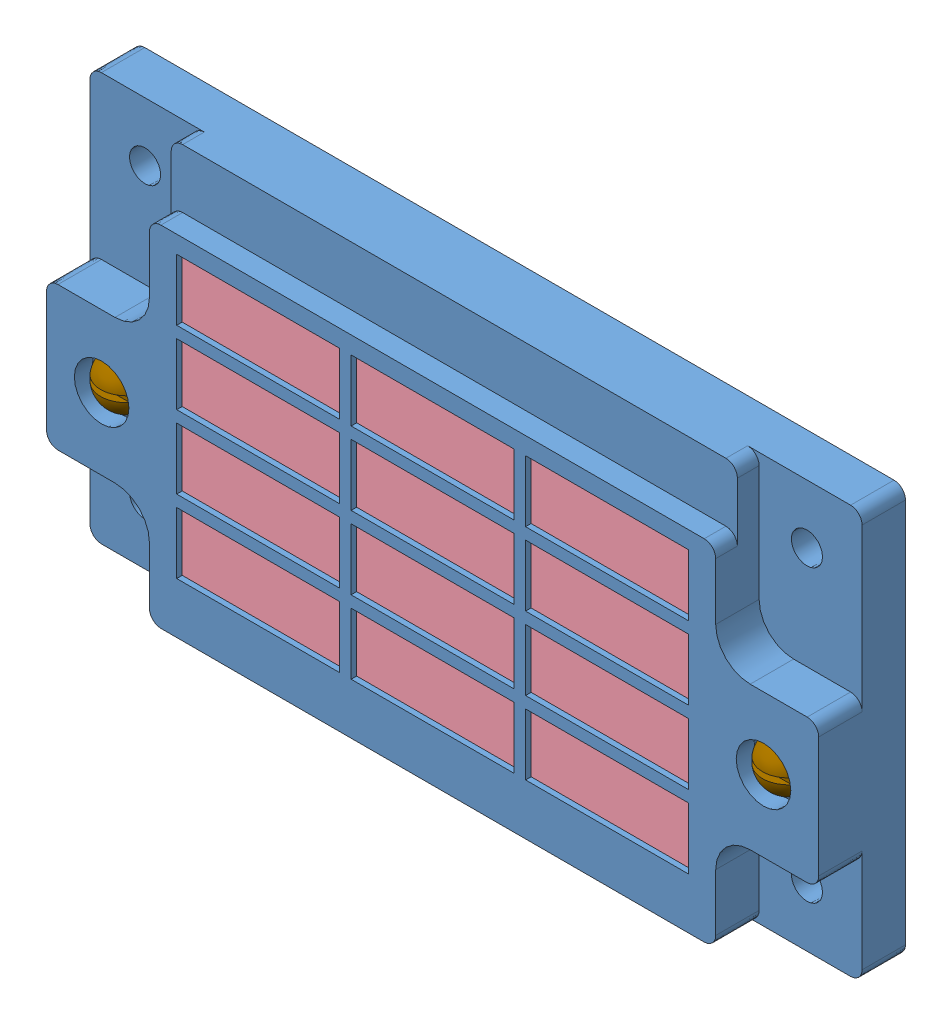
SolidWorks assembly Caution Lights Panel, configuration Default. Lengths in mm.
Overall size (106.68 56.39 15.2).
72 component instances, 9 part files, 31 mates.
Components (placement in the parent):
- Caution Lights Panel Chassis-1: Caution Lights Panel Chassis [Default] at origin size (106.68 56.39 12)
- Caution Lights Panel Legend Diffuser-1: Caution Lights Panel Legend Diffuser [Amber] at (0 0 10.349) x (-1 0 0) z (0 0 -1) size (23.01 9.01 0.13)
- Caution Lights Panel Legend Diffuser-2: Caution Lights Panel Legend Diffuser [Amber] at (0 10.1092 10.349) x (-1 0 0) z (0 0 -1) size (23.01 9.01 0.13)
- Caution Lights Panel Legend Diffuser-3: Caution Lights Panel Legend Diffuser [Amber] at (0 20.2184 10.349) x (-1 0 0) z (0 0 -1) size (23.01 9.01 0.13)
- Caution Lights Panel Legend Diffuser-4: Caution Lights Panel Legend Diffuser [Amber] at (0 30.3276 10.349) x (-1 0 0) z (0 0 -1) size (23.01 9.01 0.13)
- Caution Lights Panel Legend Diffuser-5: Caution Lights Panel Legend Diffuser [Amber] at (-24.1046 0 10.349) x (-1 0 0) z (0 0 -1) size (23.01 9.01 0.13)
- Caution Lights Panel Legend Diffuser-6: Caution Lights Panel Legend Diffuser [Amber] at (-24.1046 10.1092 10.349) x (-1 0 0) z (0 0 -1) size (23.01 9.01 0.13)
- Caution Lights Panel Legend Diffuser-7: Caution Lights Panel Legend Diffuser [Amber] at (-24.1046 20.2184 10.349) x (-1 0 0) z (0 0 -1) size (23.01 9.01 0.13)
- Caution Lights Panel Legend Diffuser-8: Caution Lights Panel Legend Diffuser [Amber] at (-24.1046 30.3276 10.349) x (-1 0 0) z (0 0 -1) size (23.01 9.01 0.13)
- Caution Lights Panel Legend Diffuser-9: Caution Lights Panel Legend Diffuser [Amber] at (-48.2092 0 10.349) x (-1 0 0) z (0 0 -1) size (23.01 9.01 0.13)
- Caution Lights Panel Legend Diffuser-10: Caution Lights Panel Legend Diffuser [Amber] at (-48.2092 10.1092 10.349) x (-1 0 0) z (0 0 -1) size (23.01 9.01 0.13)
- Caution Lights Panel Legend Diffuser-11: Caution Lights Panel Legend Diffuser [Amber] at (-48.2092 20.2184 10.349) x (-1 0 0) z (0 0 -1) size (23.01 9.01 0.13)
- Caution Lights Panel Legend Diffuser-12: Caution Lights Panel Legend Diffuser [Amber] at (-48.2092 30.3276 10.349) x (-1 0 0) z (0 0 -1) size (23.01 9.01 0.13)
- Caution Lights Panel Legend-1: Caution Lights Panel Legend [CK SEAT] at (0 0 10.476) x (-1 0 0) z (0 0 -1) size (23.01 9.01 0.13)
- Caution Lights Panel Legend-2: Caution Lights Panel Legend [FCS HOT] at (0 10.1092 10.476) x (-1 0 0) z (0 0 -1) size (23.01 9.01 0.13)
- Caution Lights Panel Legend-3: Caution Lights Panel Legend [FUEL LO] at (0 20.2184 10.476) x (-1 0 0) z (0 0 -1) size (23.01 9.01 0.13)
- Caution Lights Panel Legend-4: Caution Lights Panel Legend [L GEN] at (0 30.3276 10.476) x (-1 0 0) z (0 0 -1) size (23.01 9.01 0.13)
- Caution Lights Panel Legend-5: Caution Lights Panel Legend [APU ACC] at (-24.1046 0 10.476) x (-1 0 0) z (0 0 -1) size (23.01 9.01 0.13)
- Caution Lights Panel Legend-6: Caution Lights Panel Legend [GEN TIE] at (-24.1046 10.1092 10.476) x (-1 0 0) z (0 0 -1) size (23.01 9.01 0.13)
- Caution Lights Panel Legend-7: Caution Lights Panel Legend [FCES] at (-24.1046 20.2184 10.476) x (-1 0 0) z (0 0 -1) size (23.01 9.01 0.13)
- Caution Lights Panel Legend-8: Caution Lights Panel Legend [R GEN] at (-24.1046 30.3276 10.476) x (-1 0 0) z (0 0 -1) size (23.01 9.01 0.13)
- Caution Lights Panel Legend-9: Caution Lights Panel Legend [BATT SW] at (-48.2092 0 10.476) x (-1 0 0) z (0 0 -1) size (23.01 9.01 0.13)
- Caution Lights Panel Legend-10: Caution Lights Panel Legend [BLANK] at (-48.2092 10.1092 10.476) x (-1 0 0) z (0 0 -1) size (23.01 9.01 0.13)
- Caution Lights Panel Legend-11: Caution Lights Panel Legend [BLANK] at (-48.2092 20.2184 10.476) x (-1 0 0) z (0 0 -1) size (23.01 9.01 0.13)
- Caution Lights Panel Legend-12: Caution Lights Panel Legend [BLANK] at (-48.2092 30.3276 10.476) x (-1 0 0) z (0 0 -1) size (23.01 9.01 0.13)
- Caution Lights Panel Legend Cover-1: Caution Lights Panel Legend Cover [Default] at (0 0 11.238) x (-1 0 0) z (0 0 -1) size (23.01 9.01 0.76)
- Caution Lights Panel Legend Cover-2: Caution Lights Panel Legend Cover [Default] at (0 10.1092 11.238) x (-1 0 0) z (0 0 -1) size (23.01 9.01 0.76)
- Caution Lights Panel Legend Cover-3: Caution Lights Panel Legend Cover [Default] at (0 20.2184 11.238) x (-1 0 0) z (0 0 -1) size (23.01 9.01 0.76)
- Caution Lights Panel Legend Cover-4: Caution Lights Panel Legend Cover [Default] at (0 30.3276 11.238) x (-1 0 0) z (0 0 -1) size (23.01 9.01 0.76)
- Caution Lights Panel Legend Cover-5: Caution Lights Panel Legend Cover [Default] at (-24.1046 0 11.238) x (-1 0 0) z (0 0 -1) size (23.01 9.01 0.76)
- Caution Lights Panel Legend Cover-6: Caution Lights Panel Legend Cover [Default] at (-24.1046 10.1092 11.238) x (-1 0 0) z (0 0 -1) size (23.01 9.01 0.76)
- Caution Lights Panel Legend Cover-7: Caution Lights Panel Legend Cover [Default] at (-24.1046 20.2184 11.238) x (-1 0 0) z (0 0 -1) size (23.01 9.01 0.76)
- Caution Lights Panel Legend Cover-8: Caution Lights Panel Legend Cover [Default] at (-24.1046 30.3276 11.238) x (-1 0 0) z (0 0 -1) size (23.01 9.01 0.76)
- Caution Lights Panel Legend Cover-9: Caution Lights Panel Legend Cover [Default] at (-48.2092 0 11.238) x (-1 0 0) z (0 0 -1) size (23.01 9.01 0.76)
- Caution Lights Panel Legend Cover-10: Caution Lights Panel Legend Cover [Default] at (-48.2092 10.1092 11.238) x (-1 0 0) z (0 0 -1) size (23.01 9.01 0.76)
- Caution Lights Panel Legend Cover-11: Caution Lights Panel Legend Cover [Default] at (-48.2092 20.2184 11.238) x (-1 0 0) z (0 0 -1) size (23.01 9.01 0.76)
- Caution Lights Panel Legend Cover-12: Caution Lights Panel Legend Cover [Default] at (-48.2092 30.3276 11.238) x (-1 0 0) z (0 0 -1) size (23.01 9.01 0.76)
- Caution Lights Panel PCB-1: Caution Lights Panel PCB [Default] x (-1 0 0) z (0 0 -1) size (81.88 39.82 1.59)
- IN-S63AT5UW - LED, 0603, WHITE, 3V, 5mA, 900mcd-1: IN-S63AT5UW - LED, 0603, WHITE, 3V, 5mA, 900mcd [Default] at (-3076.9848 1134.3057 0.0064) size (0.79 1.61 0.71)
- IN-S63AT5UW - LED, 0603, WHITE, 3V, 5mA, 900mcd-2: IN-S63AT5UW - LED, 0603, WHITE, 3V, 5mA, 900mcd [Default] at (-3087.2928 1134.3057 0.0064) size (0.79 1.61 0.71)
- IN-S63AT5UW - LED, 0603, WHITE, 3V, 5mA, 900mcd-3: IN-S63AT5UW - LED, 0603, WHITE, 3V, 5mA, 900mcd [Default] at (-3087.2928 1144.4149 0.0064) size (0.79 1.61 0.71)
- IN-S63AT5UW - LED, 0603, WHITE, 3V, 5mA, 900mcd-4: IN-S63AT5UW - LED, 0603, WHITE, 3V, 5mA, 900mcd [Default] at (-3087.2928 1154.5241 0.0064) size (0.79 1.61 0.71)
- IN-S63AT5UW - LED, 0603, WHITE, 3V, 5mA, 900mcd-5: IN-S63AT5UW - LED, 0603, WHITE, 3V, 5mA, 900mcd [Default] at (-3087.2928 1164.6333 0.0064) size (0.79 1.61 0.71)
- IN-S63AT5UW - LED, 0603, WHITE, 3V, 5mA, 900mcd-6: IN-S63AT5UW - LED, 0603, WHITE, 3V, 5mA, 900mcd [Default] at (-3111.3974 1134.3057 0.0064) size (0.79 1.61 0.71)
- IN-S63AT5UW - LED, 0603, WHITE, 3V, 5mA, 900mcd-7: IN-S63AT5UW - LED, 0603, WHITE, 3V, 5mA, 900mcd [Default] at (-3111.3974 1144.4149 0.0064) size (0.79 1.61 0.71)
- IN-S63AT5UW - LED, 0603, WHITE, 3V, 5mA, 900mcd-8: IN-S63AT5UW - LED, 0603, WHITE, 3V, 5mA, 900mcd [Default] at (-3111.3974 1154.5241 0.0064) size (0.79 1.61 0.71)
- IN-S63AT5UW - LED, 0603, WHITE, 3V, 5mA, 900mcd-9: IN-S63AT5UW - LED, 0603, WHITE, 3V, 5mA, 900mcd [Default] at (-3111.3974 1164.6333 0.0064) size (0.79 1.61 0.71)
- IN-S63AT5UW - LED, 0603, WHITE, 3V, 5mA, 900mcd-10: IN-S63AT5UW - LED, 0603, WHITE, 3V, 5mA, 900mcd [Default] at (-3135.502 1134.3057 0.0064) size (0.79 1.61 0.71)
- IN-S63AT5UW - LED, 0603, WHITE, 3V, 5mA, 900mcd-11: IN-S63AT5UW - LED, 0603, WHITE, 3V, 5mA, 900mcd [Default] at (-3135.502 1144.4149 0.0064) size (0.79 1.61 0.71)
- IN-S63AT5UW - LED, 0603, WHITE, 3V, 5mA, 900mcd-12: IN-S63AT5UW - LED, 0603, WHITE, 3V, 5mA, 900mcd [Default] at (-3135.502 1154.5241 0.0064) size (0.79 1.61 0.71)
- IN-S63AT5UW - LED, 0603, WHITE, 3V, 5mA, 900mcd-13: IN-S63AT5UW - LED, 0603, WHITE, 3V, 5mA, 900mcd [Default] at (-3135.502 1164.6333 0.0064) size (0.79 1.61 0.71)
- IN-S63AT5UW - LED, 0603, WHITE, 3V, 5mA, 900mcd-14: IN-S63AT5UW - LED, 0603, WHITE, 3V, 5mA, 900mcd [Default] at (-3076.9848 1144.4149 0.0064) size (0.79 1.61 0.71)
- IN-S63AT5UW - LED, 0603, WHITE, 3V, 5mA, 900mcd-15: IN-S63AT5UW - LED, 0603, WHITE, 3V, 5mA, 900mcd [Default] at (-3076.9848 1154.5241 0.0064) size (0.79 1.61 0.71)
- IN-S63AT5UW - LED, 0603, WHITE, 3V, 5mA, 900mcd-16: IN-S63AT5UW - LED, 0603, WHITE, 3V, 5mA, 900mcd [Default] at (-3076.9848 1164.6333 0.0064) size (0.79 1.61 0.71)
- IN-S63AT5UW - LED, 0603, WHITE, 3V, 5mA, 900mcd-17: IN-S63AT5UW - LED, 0603, WHITE, 3V, 5mA, 900mcd [Default] at (-3101.0894 1134.3057 0.0064) size (0.79 1.61 0.71)
- IN-S63AT5UW - LED, 0603, WHITE, 3V, 5mA, 900mcd-18: IN-S63AT5UW - LED, 0603, WHITE, 3V, 5mA, 900mcd [Default] at (-3101.0894 1144.4149 0.0064) size (0.79 1.61 0.71)
- IN-S63AT5UW - LED, 0603, WHITE, 3V, 5mA, 900mcd-19: IN-S63AT5UW - LED, 0603, WHITE, 3V, 5mA, 900mcd [Default] at (-3101.0894 1154.5241 0.0064) size (0.79 1.61 0.71)
- IN-S63AT5UW - LED, 0603, WHITE, 3V, 5mA, 900mcd-20: IN-S63AT5UW - LED, 0603, WHITE, 3V, 5mA, 900mcd [Default] at (-3101.0894 1164.6333 0.0064) size (0.79 1.61 0.71)
- IN-S63AT5UW - LED, 0603, WHITE, 3V, 5mA, 900mcd-21: IN-S63AT5UW - LED, 0603, WHITE, 3V, 5mA, 900mcd [Default] at (-3125.194 1134.3057 0.0064) size (0.79 1.61 0.71)
- IN-S63AT5UW - LED, 0603, WHITE, 3V, 5mA, 900mcd-22: IN-S63AT5UW - LED, 0603, WHITE, 3V, 5mA, 900mcd [Default] at (-3125.194 1144.4149 0.0064) size (0.79 1.61 0.71)
- IN-S63AT5UW - LED, 0603, WHITE, 3V, 5mA, 900mcd-23: IN-S63AT5UW - LED, 0603, WHITE, 3V, 5mA, 900mcd [Default] at (-3125.194 1154.5241 0.0064) size (0.79 1.61 0.71)
- IN-S63AT5UW - LED, 0603, WHITE, 3V, 5mA, 900mcd-24: IN-S63AT5UW - LED, 0603, WHITE, 3V, 5mA, 900mcd [Default] at (-3125.194 1164.6333 0.0064) size (0.79 1.61 0.71)
- 93365A110_BRASS HEAT-SET INSERT FOR PLASTICS_2-56-1: 93365A110_BRASS HEAT-SET INSERT FOR PLASTICS_2-56 [Default] at (-3067.85 1166.8237 0) x (-0.923728 -0.383049 0) z (0.383049 -0.923728 0) size (3.58 3.09 3.58)
- 93365A110_BRASS HEAT-SET INSERT FOR PLASTICS_2-56-2: 93365A110_BRASS HEAT-SET INSERT FOR PLASTICS_2-56 [Default] at (-3067.85 1132.0877 0) x (-0.85131 -0.524663 0) z (0.524663 -0.85131 0) size (3.58 3.09 3.58)
- 93365A110_BRASS HEAT-SET INSERT FOR PLASTICS_2-56-3: 93365A110_BRASS HEAT-SET INSERT FOR PLASTICS_2-56 [Default] at (-3144.6368 1132.0877 0) x (-0.777574 -0.628792 0) z (0.628792 -0.777574 0) size (3.58 3.09 3.58)
- 93365A110_BRASS HEAT-SET INSERT FOR PLASTICS_2-56-4: 93365A110_BRASS HEAT-SET INSERT FOR PLASTICS_2-56 [Default] at (-3144.6368 1166.8237 0) x (-0.715577 -0.698533 0) z (0.698533 -0.715577 0) size (3.58 3.09 3.58)
- 94070A076 - PHS, 2-56 X .1875, BRASS-1: 94070A076 - PHS, 2-56 X .1875, BRASS [94070A076] at (-3144.6368 1132.0877 3.175) x (-0.923728 -0.383049 0) z (0 0 -1) size (4.24 4.24 6.25)
- 94070A076 - PHS, 2-56 X .1875, BRASS-2: 94070A076 - PHS, 2-56 X .1875, BRASS [94070A076] at (-3067.8408 1132.0877 3.175) x (-0.85131 -0.524663 0) z (0 0 -1) size (4.24 4.24 6.25)
- 94070A076 - PHS, 2-56 X .1875, BRASS-3: 94070A076 - PHS, 2-56 X .1875, BRASS [94070A076] at (-3067.8408 1166.8237 3.175) x (-0.777574 -0.628792 0) z (0 0 -1) size (4.24 4.24 6.25)
- 94070A076 - PHS, 2-56 X .1875, BRASS-4: 94070A076 - PHS, 2-56 X .1875, BRASS [94070A076] at (-3144.6368 1166.8237 3.175) x (-0.715577 -0.698533 0) z (0 0 -1) size (4.24 4.24 6.25)
- 90276A143 - RHS, SLOTTED, 6-32 X .1875, STEEL, ZINC-PLATED-1: 90276A143 - RHS, SLOTTED, 6-32 X .1875, STEEL, ZINC-PLATED [90276A143] at (-3151.9588 1147.1257 9.5362) size (6.6 6.6 7.62)
- 90276A143 - RHS, SLOTTED, 6-32 X .1875, STEEL, ZINC-PLATED-2: 90276A143 - RHS, SLOTTED, 6-32 X .1875, STEEL, ZINC-PLATED [90276A143] at (-3060.5188 1147.1257 9.5362) size (6.6 6.6 7.62)
Mates (geometry in assembly coordinates):
- InPlace1: in place: plane of Caution Lights Panel Chassis-1 through (-3054.4863 1124.5832 0) normal (0 0 -1); plane of Caution Lights Panel PCB-1 through (0 0 0) normal (0 0 -1); moOrthogonalPlaneRef_w of Caution Lights Panel Chassis-1 through (-3054.4863 1124.5832 0) normal (0 0 -1); line of Caution Lights Panel PCB-1 through (-55 0 0) axis (0 0 1); plane of Caution Lights Panel Chassis-1 through (-3054.4863 1124.5832 0) normal (0 0 -1); plane of Caution Lights Panel PCB-1 through (0 0 0) normal (-1 0 0); plane of Caution Lights Panel Chassis-1 through (-3054.4863 1124.5832 0) normal (0 0 -1); unknown of Caution Lights Panel PCB-1
- Coincident1: coincident aligned: plane of Caution Lights Panel Chassis-1; plane of Caution Lights Panel PCB-1
- Coincident2: coincident aligned: moOrthogonalPlaneRef_w of Caution Lights Panel Chassis-1 through (0 0 0) normal (0 1 0); plane of Caution Lights Panel PCB-1 through (0 0 0) normal (0 1 0)
- Coincident3: coincident anti-aligned: moOrthogonalPlaneRef_w of Caution Lights Panel Chassis-1 through (0 0 0) normal (1 0 0); plane of Caution Lights Panel PCB-1 through (0 0 0) normal (-1 0 0)
- Concentric1: concentric aligned: cone of Caution Lights Panel Chassis-1 through (-3067.85 1166.8237 0) axis (0 0 1); cone of 93365A110_BRASS HEAT-SET INSERT FOR PLASTICS_2-56-1 through (-3067.85 1166.8237 1.11) axis (0 0 1)
- Coincident4: coincident aligned: plane of Caution Lights Panel Chassis-1 through (-3054.4863 1124.5832 0) normal (0 0 -1); plane of 93365A110_BRASS HEAT-SET INSERT FOR PLASTICS_2-56-1 through (-3066.1958 1167.5096 0) normal (0 0 -1)
- Concentric2: concentric aligned: cone of Caution Lights Panel Chassis-1 through (-3067.85 1132.0877 0) axis (0 0 1); cone of 93365A110_BRASS HEAT-SET INSERT FOR PLASTICS_2-56-2 through (-3067.85 1132.0877 1.11) axis (0 0 1)
- Coincident5: coincident aligned: plane of Caution Lights Panel Chassis-1 through (-3054.4863 1124.5832 0) normal (0 0 -1); plane of 93365A110_BRASS HEAT-SET INSERT FOR PLASTICS_2-56-2 through (-3066.3255 1133.0272 0) normal (0 0 -1)
- Concentric3: concentric aligned: cone of Caution Lights Panel Chassis-1 through (-3144.6368 1132.0877 0) axis (0 0 1); cone of 93365A110_BRASS HEAT-SET INSERT FOR PLASTICS_2-56-3 through (-3144.6368 1132.0877 1.11) axis (0 0 1)
- Coincident6: coincident aligned: plane of Caution Lights Panel Chassis-1 through (-3054.4863 1124.5832 0) normal (0 0 -1); plane of 93365A110_BRASS HEAT-SET INSERT FOR PLASTICS_2-56-3 through (-3143.2444 1133.2137 0) normal (0 0 -1)
- Concentric4: concentric aligned: cone of Caution Lights Panel Chassis-1 through (-3144.6368 1166.8237 0) axis (0 0 1); cone of 93365A110_BRASS HEAT-SET INSERT FOR PLASTICS_2-56-4 through (-3144.6368 1166.8237 1.11) axis (0 0 1)
- Coincident7: coincident aligned: plane of Caution Lights Panel Chassis-1 through (-3054.4863 1124.5832 0) normal (0 0 -1); plane of 93365A110_BRASS HEAT-SET INSERT FOR PLASTICS_2-56-4 through (-3143.3554 1168.0746 0) normal (0 0 -1)
- Concentric5: concentric anti-aligned: cylinder of Caution Lights Panel PCB-1 through (-3144.6368 1132.0877 -1.5875) axis (0 0 -1) radius 1.35; cylinder of 94070A076 - PHS, 2-56 X .1875, BRASS-1 through (-3144.6368 1132.0877 3.175) axis (0 0 1) radius 2.1209
- Coincident8: coincident anti-aligned: plane of Caution Lights Panel PCB-1 through (0 0 -1.5875) normal (0 0 -1); plane of 94070A076 - PHS, 2-56 X .1875, BRASS-1 through (-3144.6368 1132.0877 -1.5875) normal (0 0 1)
- Concentric6: concentric anti-aligned: cylinder of Caution Lights Panel PCB-1 through (-3067.8408 1132.0877 -1.5875) axis (0 0 -1) radius 1.35; cylinder of 94070A076 - PHS, 2-56 X .1875, BRASS-2 through (-3067.8408 1132.0877 3.175) axis (0 0 1) radius 2.1209
- Coincident9: coincident anti-aligned: plane of Caution Lights Panel PCB-1 through (0 0 -1.5875) normal (0 0 -1); plane of 94070A076 - PHS, 2-56 X .1875, BRASS-2 through (-3067.8408 1132.0877 -1.5875) normal (0 0 1)
- Concentric7: concentric anti-aligned: cylinder of Caution Lights Panel PCB-1 through (-3067.8408 1166.8237 -1.5875) axis (0 0 -1) radius 1.35; cylinder of 94070A076 - PHS, 2-56 X .1875, BRASS-3 through (-3067.8408 1166.8237 3.175) axis (0 0 1) radius 2.1209
- Coincident10: coincident anti-aligned: plane of Caution Lights Panel PCB-1 through (0 0 -1.5875) normal (0 0 -1); plane of 94070A076 - PHS, 2-56 X .1875, BRASS-3 through (-3067.8408 1166.8237 -1.5875) normal (0 0 1)
- Concentric8: concentric anti-aligned: cylinder of Caution Lights Panel PCB-1 through (-3144.6368 1166.8237 -1.5875) axis (0 0 -1) radius 1.35; cylinder of 94070A076 - PHS, 2-56 X .1875, BRASS-4 through (-3144.6368 1166.8237 3.175) axis (0 0 1) radius 2.1209
- Coincident11: coincident anti-aligned: plane of Caution Lights Panel PCB-1 through (0 0 -1.5875) normal (0 0 -1); plane of 94070A076 - PHS, 2-56 X .1875, BRASS-4 through (-3144.6368 1166.8237 -1.5875) normal (0 0 1)
- Coincident12: coincident anti-aligned: plane of Caution Lights Panel PCB-1 through (0 0 0) normal (0 0 1); plane of IN-S63AT5UW - LED, 0603, WHITE, 3V, 5mA, 900mcd-1 through (-3077.381 1135.1147 0) normal (0 0 -1)
- Parallel1: parallel aligned: plane of Caution Lights Panel PCB-1 through (-3065.3008 1169.3637 -1.5875) normal (1 0 0); plane of IN-S63AT5UW - LED, 0603, WHITE, 3V, 5mA, 900mcd-1 through (-3076.5911 1135.0994 0.2984) normal (1 0 0)
- Width1: width anti-aligned: plane of Caution Lights Panel Legend-1 through (-3070.6348 1129.8017 10.349) normal (0 -1 0); plane of Caution Lights Panel Legend-1 through (-3093.6428 1138.8097 10.349) normal (0 1 0); plane of IN-S63AT5UW - LED, 0603, WHITE, 3V, 5mA, 900mcd-1 through (-3077.381 1135.1058 0.3109) normal (0 1 0); plane of IN-S63AT5UW - LED, 0603, WHITE, 3V, 5mA, 900mcd-1 through (-3077.381 1133.5056 0.3109) normal (0 -1 0)
- Distance1: distance = 6.35 mm aligned: plane of IN-S63AT5UW - LED, 0603, WHITE, 3V, 5mA, 900mcd-1 through (-3076.9848 1134.3057 0.0064) normal (1 0 0); plane of Caution Lights Panel Legend-1 through (-3070.6348 1138.8097 10.349) normal (1 0 0)
- Coincident14: coincident aligned: plane of IN-S63AT5UW - LED, 0603, WHITE, 3V, 5mA, 900mcd-1 through (-3077.3942 1133.8352 0.7074) normal (0 0 1); plane of IN-S63AT5UW - LED, 0603, WHITE, 3V, 5mA, 900mcd-2 through (-3087.7022 1133.8352 0.7074) normal (0 0 1)
- Coincident15: coincident aligned: plane of IN-S63AT5UW - LED, 0603, WHITE, 3V, 5mA, 900mcd-1 through (-3077.3942 1133.7594 0.2943) normal (0 -0.99863 0.052336); plane of IN-S63AT5UW - LED, 0603, WHITE, 3V, 5mA, 900mcd-2 through (-3087.7022 1133.7594 0.2943) normal (0 -0.99863 0.052336)
- Distance2: distance = 6.35 mm anti-aligned: plane of IN-S63AT5UW - LED, 0603, WHITE, 3V, 5mA, 900mcd-2 through (-3087.2928 1134.3057 0.0064) normal (1 0 0); plane of Caution Lights Panel Legend-1 through (-3093.6428 1129.8017 10.349) normal (-1 0 0)
- Concentric10: concentric anti-aligned: cylinder of Caution Lights Panel Chassis-1 through (-3151.9588 1147.1257 12) axis (0 0 1) radius 3.7706; cylinder of 90276A143 - RHS, SLOTTED, 6-32 X .1875, STEEL, ZINC-PLATED-1 through (-3151.9588 1147.1257 12.1524) axis (0 0 -1) radius 3.302
- Coincident17: coincident anti-aligned: plane of Caution Lights Panel Chassis-1 through (-3149.8061 1147.1257 9.5362) normal (0 0 1); plane of 90276A143 - RHS, SLOTTED, 6-32 X .1875, STEEL, ZINC-PLATED-1 through (-3151.9588 1147.1257 9.5362) normal (0 0 -1)
- Concentric11: concentric anti-aligned: cylinder of Caution Lights Panel Chassis-1 through (-3060.5188 1147.1257 12) axis (0 0 1) radius 3.7706; cylinder of 90276A143 - RHS, SLOTTED, 6-32 X .1875, STEEL, ZINC-PLATED-2 through (-3060.5188 1147.1257 12.1524) axis (0 0 -1) radius 3.302
- Coincident18: coincident anti-aligned: plane of Caution Lights Panel Chassis-1 through (-3058.3661 1147.1257 9.5362) normal (0 0 1); plane of 90276A143 - RHS, SLOTTED, 6-32 X .1875, STEEL, ZINC-PLATED-2 through (-3060.5188 1147.1257 9.5362) normal (0 0 -1)
